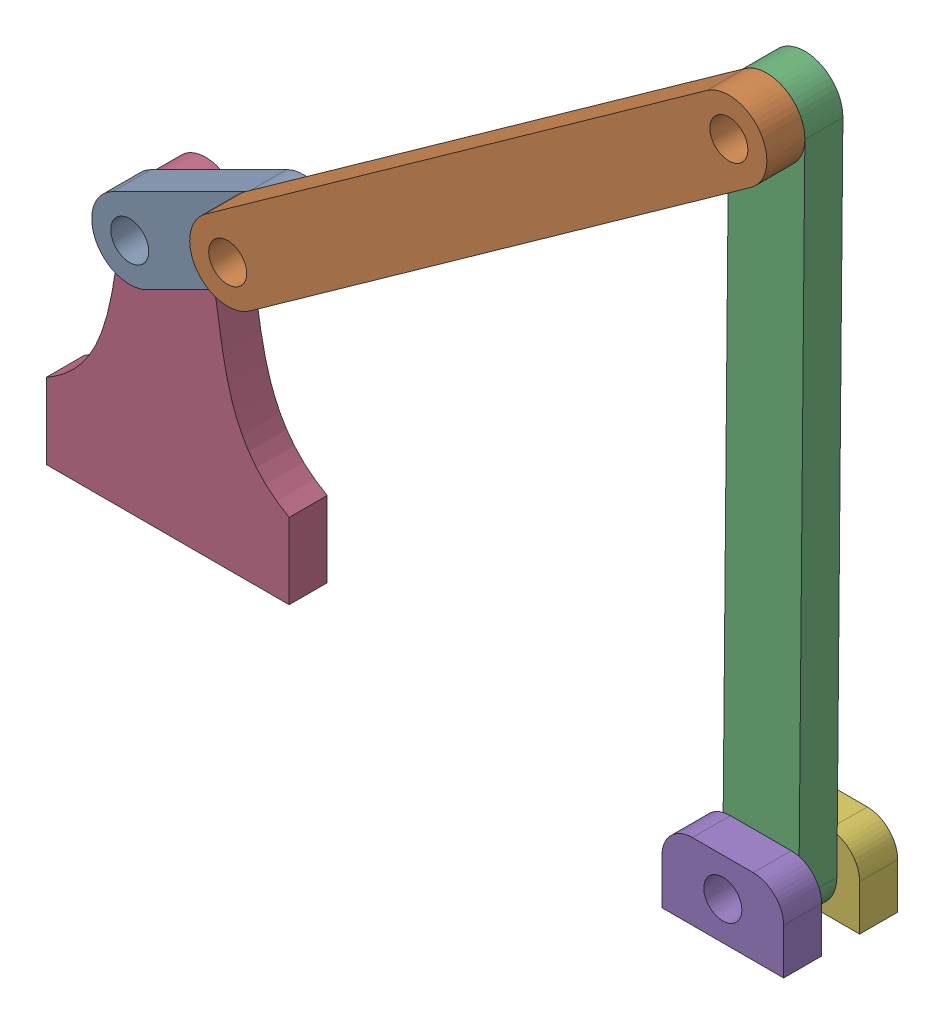
SolidWorks assembly linkage_assem_for_automata, configuration Default. Lengths in mm.
Overall size (135.89 125.75 19.05).
6 component instances, 5 part files, 14 mates.
Components (placement in the parent):
- link1_test-1: link1_test [Default] at (-115.6049 45.72 33.3608) x (0.447456 -0.894306 0) z (0 0 1) size (12.7 38.1 6.35)
- link2-1: link2 [Default] at (-92.8895 57.0854 39.7108) x (0.58083 -0.814025 0) z (0 0 1) size (12.7 115.57 6.35)
- link3-1: link3 [Default] at (-10.16 6.35 33.3608) x (0.999958 -0.009134 0) z (0 0 1) size (12.7 123.19 6.35)
- stand-1: stand [Default] at (-115.6049 0 27.0108) size (40.57 51.44 6.35)
- small_stand-1: small_stand [Default] at (-20.32 0 39.7108) size (20.32 12.7 6.35)
- small_stand-2: small_stand [Default] at (-20.32 0 27.0108) size (20.32 12.7 6.35)
Mates (geometry in assembly coordinates):
- Coincident13: coincident anti-aligned: plane of stand-1 through (-95.32 0 33.3608) normal (0 -1 0)
- Coincident15: coincident anti-aligned: plane of small_stand-1 through (-20.32 0 46.0608) normal (0 -1 0)
- Coincident17: coincident aligned: plane of stand-1 through (-125.2786 28.6354 33.3608) normal (0 0 1); plane of small_stand-2 through (-15.24 7.62 33.3608) normal (0 0 1)
- Distance1: distance = 75 mm anti-aligned: plane of small_stand-2 through (-20.32 0 33.3608) normal (-1 0 0); plane of stand-1 through (-95.32 0 33.3608) normal (1 0 0)
- Concentric1: concentric aligned: cylinder of link3-1 through (-10.16 6.35 39.7108) axis (0 0 -1) radius 3.175; cylinder of small_stand-2 through (-10.16 6.35 33.3608) axis (0 0 -1) radius 3.175
- Coincident19: coincident anti-aligned: plane of link3-1 through (-9.1508 116.8354 33.3608) normal (0 0 -1); plane of small_stand-2 through (-15.24 7.62 33.3608) normal (0 0 1)
- Concentric2: concentric aligned: cylinder of link1-1 through (-115.6049 45.72 39.7108) axis (0 0 -1) radius 3.175; cylinder of stand-1 through (-115.6049 45.72 33.3608) axis (0 0 -1) radius 3.175
- Coincident20: coincident anti-aligned: plane of link1-1 through (-92.8895 57.0854 33.3608) normal (0 0 -1); plane of stand-1 through (-125.2786 28.6354 33.3608) normal (0 0 1)
- Concentric3: concentric aligned: cylinder of link1-1 through (-92.8895 57.0854 39.7108) axis (0 0 -1) radius 3.175; cylinder of link2-1 through (-92.8895 57.0854 46.0608) axis (0 0 -1) radius 3.175
- Coincident21: coincident anti-aligned: plane of link1-1 through (-92.8895 57.0854 39.7108) normal (0 0 1); plane of link2-1 through (-9.1508 116.8354 39.7108) normal (0 0 -1)
- Coincident22: coincident anti-aligned: circle of link2-1; cylinder of link3-1 through (-9.1508 116.8354 39.7108) axis (0 0 -1) radius 3.175
- Coincident23: coincident anti-aligned: plane of link3-1 through (-9.1508 116.8354 39.7108) normal (0 0 1); plane of small_stand-1 through (-15.24 7.62 39.7108) normal (0 0 -1)
- Concentric5: concentric aligned: cylinder of link3-1 through (-10.16 6.35 39.7108) axis (0 0 -1) radius 3.175; cylinder of small_stand-1 through (-10.16 6.35 46.0608) axis (0 0 -1) radius 3.175
- Coincident25: coincident aligned: plane of small_stand-1 through (0 0 46.0608) normal (1 0 0)
